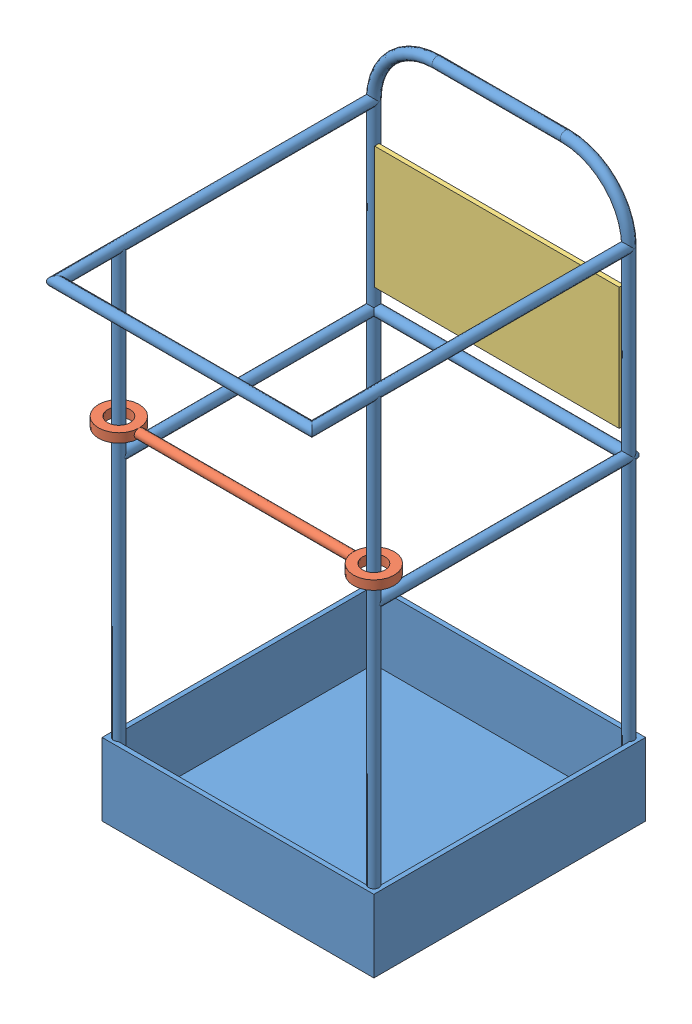
SolidWorks assembly 01, configuration Default. Lengths in mm.
Overall size (653 1251.5 730).
3 component instances, 3 part files, 5 mates.
Components (placement in the parent):
- base-1: base [Default] at (-695.0621 -529.7128 425.7796) size (600 1251.5 730)
- gaurd-1: gaurd [Default] at (-641.5621 234.5938 407.2796) x (0 0 -1) z (1 0 0) size (90 20 653)
- 01-02-1: 01-02 [Default] at (-395.0621 355.2872 -155.7204) size (540 270 10)
Mates (geometry in assembly coordinates):
- Concentric10: concentric aligned: cylinder of base-1 through (-676.5621 170.2872 407.2796) axis (0 -1 0) radius 11.5; cylinder of gaurd-1 through (-676.5621 234.5938 407.2796) axis (0 -1 0) radius 25
- Concentric11: concentric aligned: cylinder of base-1 through (-113.5621 170.2872 407.2796) axis (0 -1 0) radius 11.5; cylinder of gaurd-1 through (-113.5621 234.5938 407.2796) axis (0 -1 0) radius 25
- Coincident1: coincident: cylinder of base-1 through (-676.5621 570.2872 -155.7204) axis (0 -1 0) radius 11.5; line of 01-02-1 through (-665.0621 490.2872 -155.7204) axis (0 -1 0)
- Coincident2: coincident: cylinder of base-1 through (-113.5621 570.2872 -155.7204) axis (0 -1 0) radius 11.5; line of 01-02-1 through (-125.0621 220.2872 -155.7204) axis (0 1 0)
- Distance1: distance = 740 mm anti-aligned: plane of 01-02-1 through (-665.0621 220.2872 -145.7204) normal (0 -1 0); plane of base-1 through (-695.0621 -519.7128 425.7796) normal (0 1 0)
